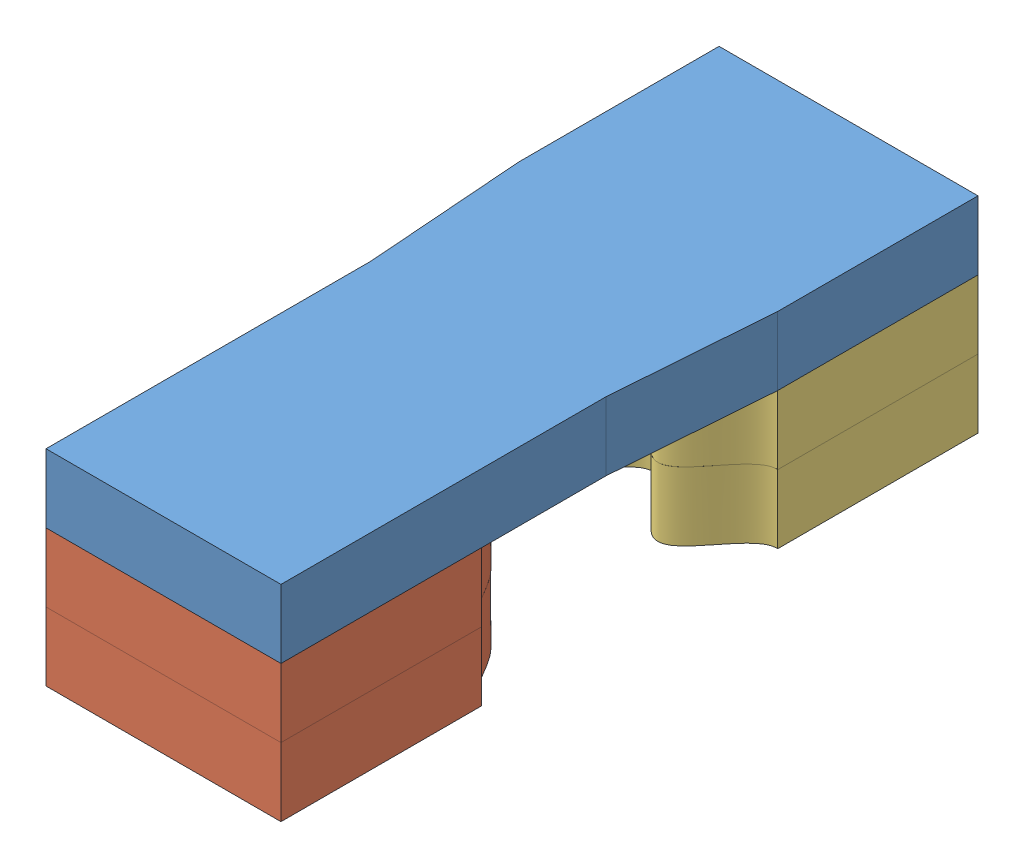
SolidWorks assembly Assem5, configuration Default. Lengths in mm.
Overall size (13.11 9 32.23).
5 component instances, 3 part files, 12 mates.
Components (placement in the parent):
- tooth-connector-1: tooth-connector [Default] at (10.0379 16.3526 22.1473) size (11.34 3 30)
- tooth-inside-1: tooth-inside [Default] at (10.0383 13.3526 101.9434) x (0.992546 0 -0.121869) z (0.121869 0 0.992546) size (11.34 3.06 12.33)
- tooth-outside-1: tooth-outside [Default] at (10.0402 13.3526 96.9687) x (0.996195 0 -0.087156) z (0.087156 0 0.996195) size (12.06 3 11.83)
- tooth-inside-2: tooth-inside [Default] at (10.0383 10.3526 101.9434) x (0.992546 0 -0.121869) z (0.121869 0 0.992546) size (11.34 3.06 12.33)
- tooth-outside-2: tooth-outside [Default] at (10.0402 10.3526 96.9687) x (0.996195 0 -0.087156) z (0.087156 0 0.996195) size (12.06 3 11.83)
Mates (geometry in assembly coordinates):
- Coincident1: coincident: plane of tooth-connector-1 through (10.0379 16.3526 22.1473) normal (0 -1 0); plane of tooth-inside-1 through (56.9823 16.3526 41.8578) normal (0 1 0)
- Coincident2: coincident: plane of tooth-connector-1 through (4.3679 19.3526 37.1473) normal (0 0 1); plane of tooth-inside-1 through (4.8937 16.3526 37.1473) normal (0 0 1)
- Coincident3: coincident: point of tooth-connector-1; point of tooth-inside-1
- Coincident4: coincident: plane of tooth-inside-1 through (56.9823 13.3526 41.8578) normal (0 -1 0); plane of tooth-inside-2 through (56.9823 13.3526 41.8578) normal (0 1 0)
- Coincident5: coincident: plane of tooth-inside-1 through (4.8937 16.3526 37.1473) normal (0 0 1); plane of tooth-inside-2 through (4.8937 13.3526 37.1473) normal (0 0 1)
- Coincident6: coincident: point of tooth-inside-1; point of tooth-inside-2
- Coincident7: coincident: plane of tooth-connector-1 through (10.0379 16.3526 22.1473) normal (0 -1 0); plane of tooth-outside-1 through (62.2665 16.3526 34.7278) normal (0 1 0)
- Coincident8: coincident: plane of tooth-connector-1 through (4.3679 19.3526 7.1473) normal (0 0 -1); plane of tooth-outside-1 through (4.3725 13.3525 7.1473) normal (0 0 -1)
- Coincident9: coincident: point of tooth-connector-1; point of tooth-outside-1
- Coincident10: coincident: plane of tooth-outside-1 through (62.2665 13.3526 34.7278) normal (0 -1 0); plane of tooth-outside-2 through (62.2665 13.3526 34.7278) normal (0 1 0)
- Coincident11: coincident: plane of tooth-outside-1 through (4.3725 13.3525 7.1473) normal (0 0 -1); plane of tooth-outside-2 through (4.3725 10.3525 7.1473) normal (0 0 -1)
- Coincident12: coincident: point of tooth-outside-1; point of tooth-outside-2
